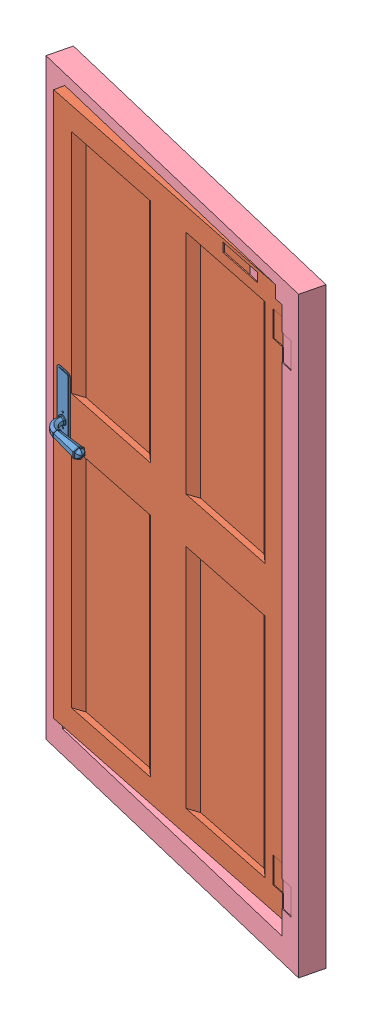
SolidWorks assembly final assembly, configuration Default. Lengths in mm.
Overall size (1506.77 2679.27 1428.93).
21 component instances, 12 part files, 9 mates.
Components (placement in the parent):
- qq-1: qq [Default] at (632.3537 -1108.2867 6312.4829) x (-0.995974 0.029469 0.084661) z (-0.077539 0.190723 -0.978577) size (1333.42 2472.06 870.76)
  - door handle 1-1: door handle 1 [Default] at (934.7683 -832.1239 7007.9411) x (0.28471 0.174662 -0.942568) z (0.958161 -0.082077 0.274211) size (85.3 269.25 234.5)
  - Door-1: Door [Default] at (461.6157 -555.9908 6912.5833) x (-0.958161 0.082077 -0.274211) z (-0.28471 -0.174662 0.942568) size (1300 2400 60)
  - door handle 2-1: door handle 2 [Default] at (919.6218 -841.416 7058.0857) x (-0.28471 -0.174662 0.942568) z (0.958161 -0.082077 0.274211) size (85.3 270 234.5)
- Part2-1: Part2 [Default] at (345.2203 559.7966 -466.7014) x (-0.972076 0 -0.234664) z (-0.234664 0 0.972076) size (1510 2610 100)
- WemosD1-1: WemosD1 [Default] at (-1007.321 -616.1016 -711.531) x (0.972076 0 0.234664) z (0.234664 0 -0.972076) size (70.96 53.34 14.5)
- Relay - 2 Channel - 2PH63091A - Montaj-1: Relay - 2 Channel - 2PH63091A - Montaj [Varsayılan] at (-959.9497 -526.2605 -700.8735) x (-0.972076 0 -0.234664) z (0 -1 0) size (39 19 51)
  - 2PH63091A Board-1: 2PH63091A Board [Varsayılan] at (-1.1106 -2.3564 51) size (39 5.5 51)
  - Relay Body-1: Relay Body [Varsayılan] at (-8.8606 -0.8564 54.25) size (15 18 19)
  - Relay Body-2: Relay Body [Varsayılan] at (6.6394 -0.8564 54.25) size (15 18 19)
  - 4 Headers-1: 4 Headers [Varsayılan] at (-6.5492 -0.8564 28.5) size (10 11 2.5)
  - Headers-1: Headers [Varsayılan] at (6.6394 -0.8564 28.5) size (7 11 2)
  - Clamp Body-3: Clamp Body [Varsayılan] at (-8.8606 4.6436 67.75) x (-1 0 0) z (0 0 -1) size (15 10.5 8)
  - Clamp Body-4: Clamp Body [Varsayılan] at (6.6394 4.6436 67.75) x (-1 0 0) z (0 0 -1) size (15 10.5 8)
  - Metal Clamp Part-7: Metal Clamp Part [Varsayılan] at (-13.8606 2.6436 68.39) size (4 11.02 6)
  - Metal Clamp Part-8: Metal Clamp Part [Varsayılan] at (-8.8606 2.6436 68.39) size (4 11.02 6)
  - Metal Clamp Part-9: Metal Clamp Part [Varsayılan] at (-3.8606 2.6436 68.39) size (4 11.02 6)
  - Metal Clamp Part-10: Metal Clamp Part [Varsayılan] at (1.6394 2.6436 68.39) size (4 11.02 6)
  - Metal Clamp Part-11: Metal Clamp Part [Varsayılan] at (6.6394 2.6436 68.39) size (4 11.02 6)
  - Metal Clamp Part-12: Metal Clamp Part [Varsayılan] at (11.6394 2.6436 68.39) size (4 11.02 6)
- ArduCAM MINI 2mp + ESP8266 Nano-2: ArduCAM MINI 2mp + ESP8266 Nano [Default] at (-966.2592 -547.4916 -778.6701) x (-0.972076 0 -0.234664) z (0.234664 0 -0.972076) size (25.5 38.61 22.13)
Mates (geometry in assembly coordinates):
- Coincident147: coincident anti-aligned: plane of Part2-1 through (322.2232 559.7966 -371.4379) normal (-0.234664 0 0.972076); plane of khoa cua 4-1 through (213.0745 683.009 -397.787) normal (0.234664 0 -0.972076)
- Coincident148: coincident: line of Part2-1 through (205.3146 631.7164 -397.6028) axis (0 -1 0); moEndPointRef_w of khoa cua 4-1
- Coincident152: coincident anti-aligned: line of Part2-1 through (-940.4676 -669.4416 -693.7463) axis (-0.972076 0 -0.234664); line of WemosD1-1 through (-1007.6964 -669.4416 -709.9757) axis (0.972076 0 0.234664)
- Coincident153: coincident anti-aligned: plane of Part2-1 through (326.2125 559.7966 -387.9632) normal (0.234664 0 -0.972076); plane of WemosD1-1 through (-975.0415 -642.6431 -702.0927) normal (-0.234664 0 0.972076)
- Coincident154: coincident: plane of Part2-1 through (-940.4676 -669.4416 -693.7463) normal (-0.972076 0 -0.234664); line of WemosD1-1 through (-939.8572 -646.5806 -696.2747) axis (0 1 0)
- Coincident155: coincident anti-aligned: plane of Part2-1 through (326.2125 559.7966 -387.9632) normal (0.234664 0 -0.972076); plane of Relay - 2 Channel - 2PH63091A - Montaj-1/2PH63091A Board-1 through (-976.4344 -600.7605 -702.4289) normal (-0.234664 0 0.972076)
- Coincident156: coincident: plane of Part2-1 through (-940.4676 -669.4416 -693.7463) normal (-0.972076 0 -0.234664); line of Relay - 2 Channel - 2PH63091A - Montaj-1/2PH63091A Board-1 through (-940.1156 -553.7605 -695.2045) axis (0 -1 0)
- Coincident158: coincident anti-aligned: line of Part2-1 through (-970.3066 -544.9416 -784.2764) axis (0 1 0); line of ArduCAM MINI 2mp + ESP8266 Nano-2 through (-970.3066 -534.4416 -784.2764) axis (0 -1 0)
- Coincident159: coincident anti-aligned: line of Part2-1 through (-970.3066 -534.4416 -784.2764) axis (0.972076 0 0.234664); line of ArduCAM MINI 2mp + ESP8266 Nano-2 through (-960.0998 -534.4416 -781.8124) axis (-0.972076 0 -0.234664)
